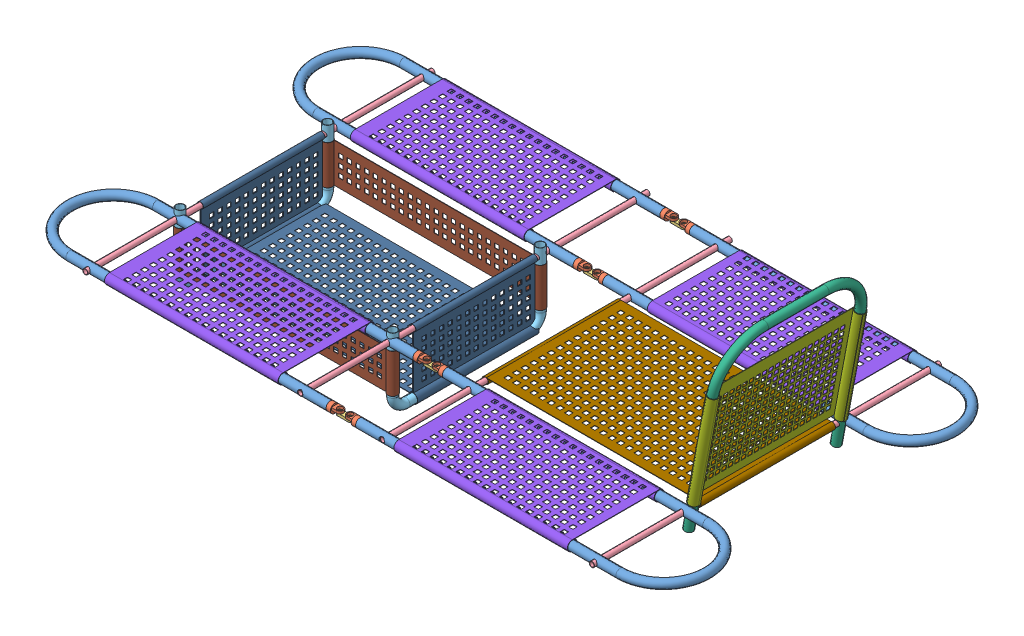
SolidWorks assembly FrameConTelas, configuration Default. Lengths in mm.
Overall size (1488 506.65 807.68).
34 component instances, 11 part files, 28 mates.
Components (placement in the parent):
- FrameOneSideNoAnim-1: FrameOneSideNoAnim [Default] at (577.8554 752.7862 1416.0585) size (1488 20 220)
  - F1-1: F1 [Default<As Welded>] at (120.0879 35.9229 252.3231) size (710 20 220)
  - H1-1: H1 [Default] at (120.0879 35.9229 252.3231) x (0 1 0) z (-1 0 0) size (20 20 40)
  - H2-1: H2 [Default] at (166.0879 29.9229 252.3231) x (1 0 0) z (0 1 0) size (36 12 6)
  - H1-2: H1 [Default] at (188.0879 35.9229 252.3231) x (0 1 0) z (1 0 0) size (20 20 40)
  - H2-2: H2 [Default] at (166.0879 29.9229 52.3231) x (1 0 0) z (0 1 0) size (36 12 6)
  - H1-4: H1 [Default] at (188.0879 35.9229 52.3231) x (0 1 0) z (1 0 0) size (20 20 40)
  - H1-6: H1 [Default] at (120.0879 35.9229 52.3231) x (0 1 0) z (-1 0 0) size (20 20 40)
  - F1-2: F1 [Default<As Welded>] at (188.0879 35.9229 52.3231) x (-1 0 0) z (0 0 -1) size (710 20 220)
- FrameOneSideNoAnim-2: FrameOneSideNoAnim [Default] at (577.8554 752.7862 846.9204) size (1488 20 220)
  - F1-1: F1 [Default<As Welded>] at (120.0879 35.9229 252.3231) size (710 20 220)
  - H1-1: H1 [Default] at (120.0879 35.9229 252.3231) x (0 1 0) z (-1 0 0) size (20 20 40)
  - H2-1: H2 [Default] at (166.0879 29.9229 252.3231) x (1 0 0) z (0 1 0) size (36 12 6)
  - H1-2: H1 [Default] at (188.0879 35.9229 252.3231) x (0 1 0) z (1 0 0) size (20 20 40)
  - H2-2: H2 [Default] at (166.0879 29.9229 52.3231) x (1 0 0) z (0 1 0) size (36 12 6)
  - H1-4: H1 [Default] at (188.0879 35.9229 52.3231) x (0 1 0) z (1 0 0) size (20 20 40)
  - H1-6: H1 [Default] at (120.0879 35.9229 52.3231) x (0 1 0) z (-1 0 0) size (20 20 40)
  - F1-2: F1 [Default<As Welded>] at (188.0879 35.9229 52.3231) x (-1 0 0) z (0 0 -1) size (710 20 220)
- F2-1: F2 [Default] at (147.9433 788.709 883.2223) x (0.974991 0.222245 0) z (0 0 1) size (12 12 800)
- F2-2: F2 [Default] at (637.9433 788.709 877.7586) x (-0.420932 0.907092 0) z (0 0 1) size (12 12 800)
- F2-3: F2 [Default] at (825.9433 788.709 876.0371) x (-0.580942 -0.813945 0) z (0 0 1) size (12 12 800)
- F2-4: F2 [Default] at (1315.9433 788.709 883.7191) x (-0.357466 -0.933926 0) z (0 0 1) size (12 12 800)
- F3-1: F3 [Default<As Welded>] at (147.9433 808.709 1464.7193) x (0 0 -1) z (1 0 0) size (400 170 20)
- F3-2: F3 [Default<As Welded>] at (637.9433 808.709 1464.7193) x (0 0 -1) z (1 0 0) size (400 170 20)
- F4-1: F4 [Default<As Welded>] at (1306.7067 739.5696 1111.2876) x (0 0 -1) z (0.982789 -0.184731 0) size (360 410 20)
- T1-1: T1 [Default] at (1317.6609 797.8471 1111.2876) x (0 0 1) z (-0.982789 0.184731 0) size (363 240 23)
- T2-1: T2 [Default] at (1270.4972 788.709 1099.2435) x (0 0 -1) z (0 1 0) size (223 400 23)
- T2-2: T2 [Default] at (186.063 788.709 899.2435) x (0 0 1) z (0 1 0) size (223 400 23)
- T2-3: T2 [Default] at (188.7365 788.709 1468.3816) x (0 0 1) z (0 1 0) size (223 400 23)
- T2-4: T2 [Default] at (855.5815 788.709 1468.3816) x (0 0 1) z (0 1 0) size (223 400 23)
- T3-1: T3 [Default] at (825.9433 788.709 1129.5821) size (505 15 310)
- T4-1: T4 [Default] at (147.9433 648.709 1138.0439) size (512 158 280)
- T5-1: T5 [Default] at (147.9433 684.6401 1124.7193) x (1 0 0) z (0 0 1) size (512 90 22)
- T5-2: T5 [Default] at (637.9433 683.336 1464.7193) x (-1 0 0) z (0 0 -1) size (512 90 22)
Mates (geometry in assembly coordinates):
- Coincident2: coincident aligned: line of FrameOneSideNoAnim-1/F1-2 through (1315.9433 788.709 1730.7992) axis (0 0 -1); line of FrameOneSideNoAnim-2/F1-2 through (1315.9433 788.709 1161.6611) axis (0 0 -1)
- Coincident3: coincident aligned: line of FrameOneSideNoAnim-1/F1-1 through (147.9433 788.709 1405.964) axis (0 0 1); line of FrameOneSideNoAnim-2/F1-1 through (147.9433 788.709 836.8259) axis (0 0 1)
- Coincident5: coincident anti-aligned: line of FrameOneSideNoAnim-1/F1-1 through (147.9433 788.709 1405.964) axis (0 0 1); line of F2-1 through (147.9433 788.709 1683.2223) axis (0 0 -1)
- Coincident6: coincident anti-aligned: line of FrameOneSideNoAnim-1/F1-1 through (637.9433 788.709 1422.8612) axis (0 0 1); line of F2-2 through (637.9433 788.709 1677.7586) axis (0 0 -1)
- Coincident7: coincident aligned: line of FrameOneSideNoAnim-1/F1-2 through (825.9433 788.709 1713.902) axis (0 0 -1); line of F2-3 through (825.9433 788.709 1676.0371) axis (0 0 -1)
- Coincident8: coincident aligned: line of FrameOneSideNoAnim-2/F1-2 through (1315.9433 788.709 1161.6611) axis (0 0 -1); line of F2-4 through (1315.9433 788.709 1683.7191) axis (0 0 -1)
- Concentric1: concentric anti-aligned: cylinder of F2-1 through (147.9433 788.709 1683.2223) axis (0 0 -1) radius 6; cylinder of F3-1 through (147.9433 788.709 1514.7193) axis (0 0 1) radius 6.35
- Concentric2: concentric anti-aligned: cylinder of F2-2 through (637.9433 788.709 1677.7586) axis (0 0 -1) radius 5; cylinder of F3-2 through (637.9433 788.709 1514.7193) axis (0 0 1) radius 6.35
- Concentric3: concentric anti-aligned: cylinder of F2-4 through (1315.9433 788.709 1683.7191) axis (0 0 -1) radius 5; cylinder of F4-1 through (1315.9433 788.709 1511.2876) axis (0 0 1) radius 6.35
- Coincident9: coincident anti-aligned: line of F4-1 through (1306.7067 739.5696 1111.2876) axis (0.184731 0.982789 0); line of T1-1 through (1361.9963 1033.7165 1111.2876) axis (-0.184731 -0.982789 0)
- Coincident10: coincident anti-aligned: line of F4-1 through (1306.7067 739.5696 1451.2876) axis (0.184731 0.982789 0); line of T1-1 through (1361.9963 1033.7165 1451.2876) axis (-0.184731 -0.982789 0)
- Concentric5: concentric aligned: cylinder of FrameOneSideNoAnim-2/F1-2 through (765.9433 788.709 1099.2435) axis (1 0 0) radius 10; cylinder of T2-1 through (870.4972 788.709 1099.2435) axis (1 0 0) radius 10.5
- Concentric6: concentric anti-aligned: cylinder of FrameOneSideNoAnim-2/F1-2 through (1365.9433 788.709 899.2435) axis (-1 0 0) radius 10; cylinder of T2-1 through (870.4972 788.709 899.2435) axis (1 0 0) radius 10.5
- Concentric7: concentric aligned: cylinder of FrameOneSideNoAnim-2/F1-1 through (697.9433 788.709 899.2435) axis (-1 0 0) radius 10; cylinder of T2-2 through (586.063 788.709 899.2435) axis (-1 0 0) radius 10.5
- Concentric8: concentric anti-aligned: cylinder of FrameOneSideNoAnim-2/F1-1 through (97.9433 788.709 1099.2435) axis (1 0 0) radius 10; cylinder of T2-2 through (586.063 788.709 1099.2435) axis (-1 0 0) radius 10.5
- Concentric9: concentric aligned: cylinder of FrameOneSideNoAnim-1/F1-1 through (697.9433 788.709 1468.3816) axis (-1 0 0) radius 10; cylinder of T2-3 through (588.7365 788.709 1468.3816) axis (-1 0 0) radius 10.5
- Concentric10: concentric anti-aligned: cylinder of FrameOneSideNoAnim-1/F1-1 through (97.9433 788.709 1668.3816) axis (1 0 0) radius 10; cylinder of T2-3 through (588.7365 788.709 1668.3816) axis (-1 0 0) radius 10.5
- Concentric11: concentric aligned: cylinder of FrameOneSideNoAnim-1/F1-2 through (1365.9433 788.709 1468.3816) axis (-1 0 0) radius 10; cylinder of T2-4 through (1255.5815 788.709 1468.3816) axis (-1 0 0) radius 11.5
- Concentric12: concentric anti-aligned: cylinder of FrameOneSideNoAnim-1/F1-2 through (765.9433 788.709 1668.3816) axis (1 0 0) radius 10; cylinder of T2-4 through (1255.5815 788.709 1668.3816) axis (-1 0 0) radius 10.5
- Concentric13: concentric aligned: cylinder of F2-3 through (825.9433 788.709 1676.0371) axis (0 0 -1) radius 6; cylinder of T3-1 through (825.9433 788.709 1439.5821) axis (0 0 -1) radius 7.5
- Concentric14: concentric aligned: cylinder of F2-4 through (1315.9433 788.709 1683.7191) axis (0 0 -1) radius 6; cylinder of T3-1 through (1315.9433 788.709 1439.5821) axis (0 0 -1) radius 7.5
- Concentric15: concentric anti-aligned: cylinder of F3-1 through (147.9433 648.709 1154.7193) axis (0 0 1) radius 10; cylinder of T4-1 through (147.9433 648.709 1418.0439) axis (0 0 -1) radius 11
- Concentric16: concentric anti-aligned: cylinder of F3-2 through (637.9433 648.709 1154.7193) axis (0 0 1) radius 10; cylinder of T4-1 through (637.9433 648.709 1418.0439) axis (0 0 -1) radius 11
- Concentric17: concentric aligned: cylinder of F2-1 through (147.9433 788.709 1683.2223) axis (0 0 -1) radius 6; cylinder of T4-1 through (147.9433 788.709 1418.0439) axis (0 0 -1) radius 6.5
- Concentric19: concentric aligned: cylinder of F3-2 through (637.9433 808.709 1124.7193) axis (0 -1 0) radius 10; cylinder of T5-1 through (637.9433 774.6401 1124.7193) axis (0 -1 0) radius 11
- Concentric20: concentric aligned: cylinder of F3-1 through (147.9433 808.709 1124.7193) axis (0 -1 0) radius 10; cylinder of T5-1 through (147.9433 774.6401 1124.7193) axis (0 -1 0) radius 11
- Concentric21: concentric anti-aligned: cylinder of F3-2 through (637.9433 678.709 1464.7193) axis (0 1 0) radius 10; cylinder of T5-2 through (637.9433 773.336 1464.7193) axis (0 -1 0) radius 10.5
- Concentric22: concentric anti-aligned: cylinder of F3-1 through (147.9433 678.709 1464.7193) axis (0 1 0) radius 10; cylinder of T5-2 through (147.9433 773.336 1464.7193) axis (0 -1 0) radius 11
